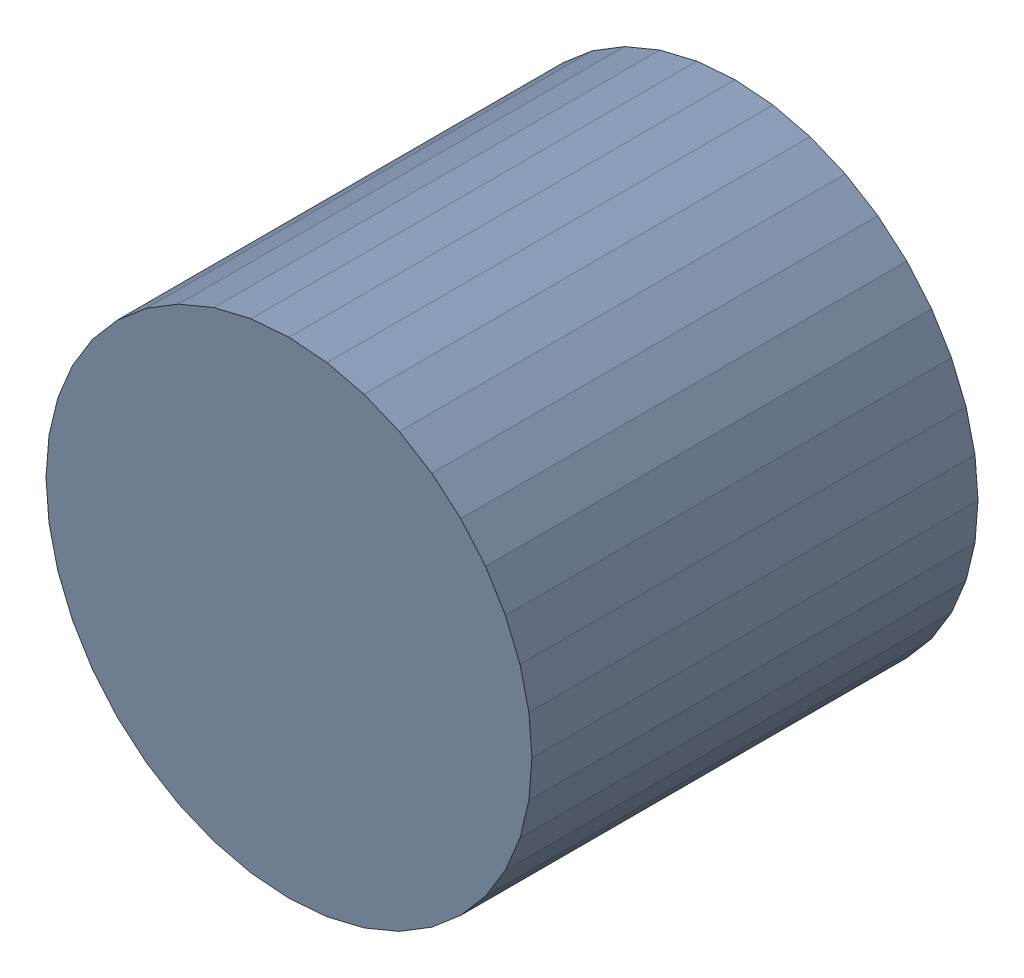
SolidWorks assembly CinSlBypKanaloa_v2.0.0_Power, configuration Default. Lengths in mm.
Overall size (6.32 6.32 5.8).
2 component instances, 1 part files, 0 mates.
Components (placement in the parent):
- 352892112-1: 352892112 [Default] at (65.35 68.45 0) size (6.32 6.32 5.8)
  - Extruded_11-1: Extruded_11 [Default] at origin size (6.32 6.32 5.8)
